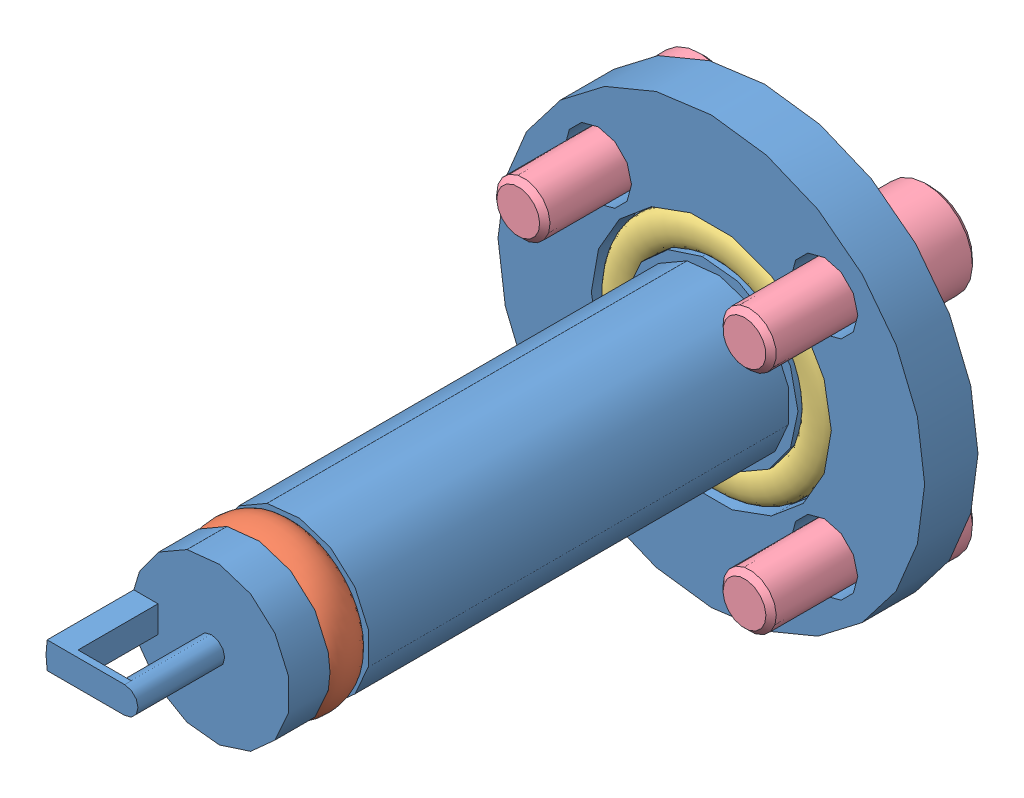
SolidWorks assembly sense_loop_assy_a_1107, configuration Default. Lengths in mm.
Overall size (32 32 60).
7 component instances, 4 part files, 8 mates.
Components (placement in the parent):
- sense_loop_a_1107-1: sense_loop_a_1107 [Default] at origin size (32 32 60)
- sense_loop_canted_1107-1: sense_loop_canted_1107 [Default] at (0 0 33) x (1 0 0) z (0 1 0) size (12 3 12)
- sense_loop_oring_1107-1: sense_loop_oring_1107 [Default] at (0 0 -0.75) x (1 0 0) z (0 1 0) size (17.5 1.5 17.5)
- Socket Head Cap Screw_AM-1: Socket Head Cap Screw_AM [B18.3.1M - 4 x 0.7 x 10 Hex SHCS -- 10NHX] at (-8.4853 -8.4853 -8) x (0 0 1) z (-0.030517 0.999534 0) size (14 7 7)
- Socket Head Cap Screw_AM-2: Socket Head Cap Screw_AM [B18.3.1M - 4 x 0.7 x 10 Hex SHCS -- 10NHX] at (-8.4853 8.4853 -8) x (0 0 1) z (0.999534 0.030517 0) size (14 7 7)
- Socket Head Cap Screw_AM-3: Socket Head Cap Screw_AM [B18.3.1M - 4 x 0.7 x 10 Hex SHCS -- 10NHX] at (8.4853 8.4853 -8) x (0 0 1) z (0.030517 -0.999534 0) size (14 7 7)
- Socket Head Cap Screw_AM-4: Socket Head Cap Screw_AM [B18.3.1M - 4 x 0.7 x 10 Hex SHCS -- 10NHX] at (8.4853 -8.4853 -8) x (0 0 1) z (-0.999534 -0.030517 0) size (14 7 7)
Mates (geometry in assembly coordinates):
- Coincident1: coincident aligned: plane of sense_loop_canted_1107-1 through (0 0 33) normal (0 1 0); plane of assembly through (0 0 0) normal (0 1 0)
- Coincident2: coincident aligned: plane of sense_loop_canted_1107-1; plane of assembly through (0 0 0) normal (1 0 0)
- Coincident3: coincident aligned: plane of sense_loop_oring_1107-1 through (0 0 -0.75) normal (0 1 0); plane of assembly through (0 0 0) normal (0 1 0)
- Coincident4: coincident aligned: plane of sense_loop_oring_1107-1; plane of assembly through (0 0 0) normal (1 0 0)
- Tangent1: tangent: plane of sense_loop_a_1107-1 through (9 0 -1.5) normal (0 0 1); face of sense_loop_oring_1107-1
- Tangent2: tangent: plane of sense_loop_a_1107-1 through (8.6418 0 34.5) normal (0 0 -1); face of sense_loop_canted_1107-1
- Coincident5: coincident anti-aligned: plane of sense_loop_a_1107-1 through (0 0 -4) normal (0 0 -1); plane of Socket Head Cap Screw_AM-1 through (-4.9869 -8.3785 -4) normal (0 0 1)
- Concentric1: concentric aligned: cylinder of sense_loop_a_1107-1 through (-8.4853 -8.4853 -4) axis (0 0 -1) radius 2.5; cylinder of Socket Head Cap Screw_AM-1 through (-8.4853 -8.4853 -39.75) axis (0 0 -1) radius 2
